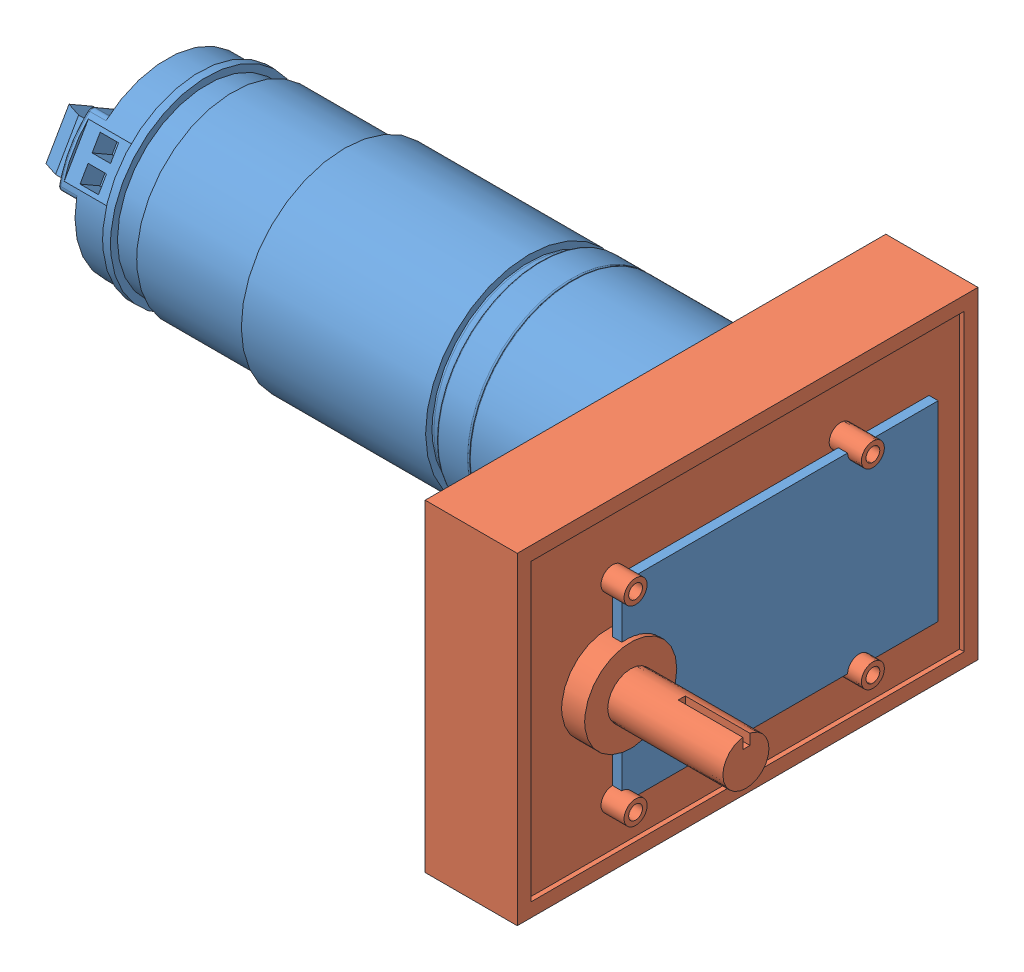
SolidWorks assembly gearbox with motor, configuration Default. Lengths in mm.
Overall size (184.5 70 100).
9 component instances, 2 part files, 0 mates.
Components (placement in the parent):
- gearbox with motor.step-1: gearbox with motor.step [Default] at origin size (184.5 70 100)
  - ss_01_3-50.step-1: ss_01_3-50.step [Default] at origin
    - BD(A16).step-1: BD(A16).step [Default] at origin (suppressed, hidden)
    - BD(A16) (1).step-1: BD(A16) (1).step [Default] at origin (suppressed, hidden)
    - BD(A16) (2).step-1: BD(A16) (2).step [Default] at origin (suppressed, hidden)
    - BD(A16) (3).step-1: BD(A16) (3).step [Default] at origin (suppressed, hidden)
    - BD(A16) (4).step-1: BD(A16) (4).step [Default] at origin (suppressed, hidden)
  - Component7.step-1: Component7.step [Default] at (-1.5 49.9941 105.3649) x (0 0 1) z (-1 0 0) size (72.82 45 158.5)
  - Component8.step-1: Component8.step [Default] at origin size (49 70 100)
